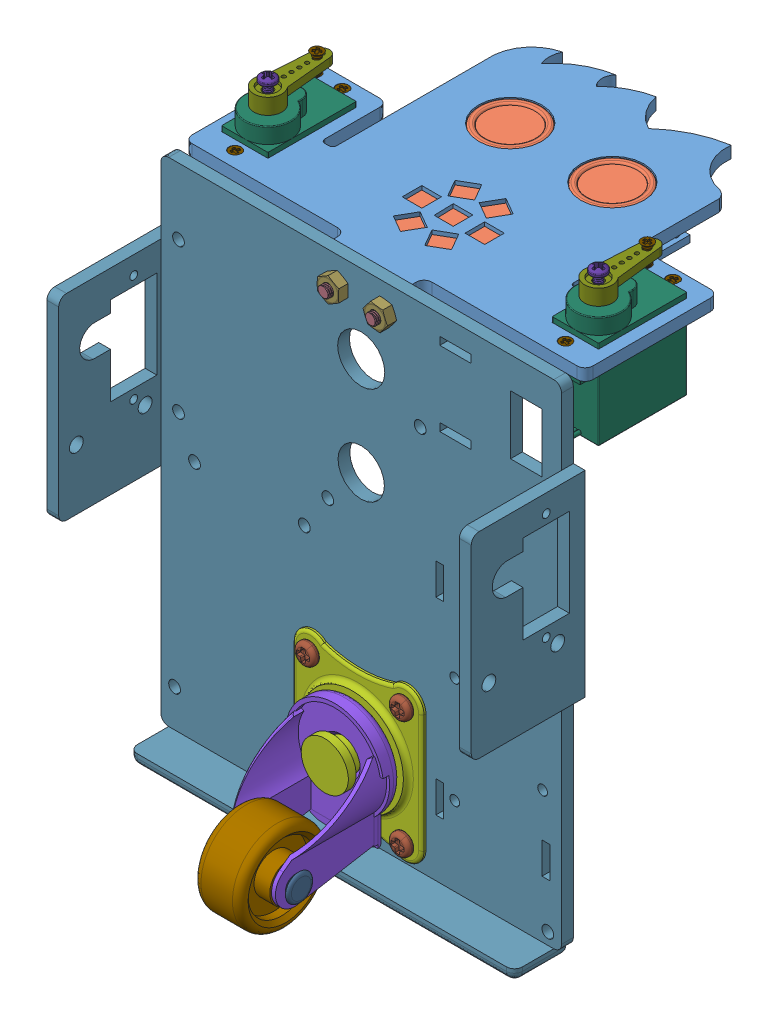
SolidWorks assembly DYOR_3D_LS_AC, configuration Predeterminado. Lengths in mm.
Overall size (108 144.05 112.97).
49 component instances, 20 part files, 16 mates.
Components (placement in the parent):
- HC-SR04 Ping Sensor-1: HC-SR04 Ping Sensor [Default] at (9.3451 28.7888 -38.4611) x (0 0 -1) z (0 1 0) size (25.18 45 18.07)
  - PCB-1: PCB [Default] at origin size (20.5 45 1.75)
  - Transducer-1: Transducer [Default] at (0 -13 13.25) x (1 0 0) z (0 -1 0) size (15.88 12 15.88)
  - Transducer-2: Transducer [Default] at (0 13 13.25) x (1 0 0) z (0 -1 0) size (15.88 12 15.88)
  - 3 Pin Header 90 Degree-1: 3 Pin Header 90 Degree [Default] at (8.4275 0 -1.25) x (-1 0 0) z (0 -1 0) size (8 7.82 10)
  - 14 Pin SMT-1: 14 Pin SMT [Default] at (-0.35 -18.5 -0.85) x (0 -1 0) z (1 0 0) size (6 1.6 8.8)
  - 14 Pin SMT-2: 14 Pin SMT [Default] at (0 -0.3826 -0.85) x (1 0 0) z (0 1 0) size (6 1.6 8.8)
  - 14 Pin SMT-3: 14 Pin SMT [Default] at (0 17.5274 -0.85) x (1 0 0) z (0 1 0) size (6 1.6 8.8)
  - Cap1 SMT-1: Cap1 SMT [Default] at (-1.755 7.4774 -0.9689) x (0 1 0) z (-1 0 0) size (4.5 1.84 1.75)
  - Cap1 SMT-2: Cap1 SMT [Default] at (6.835 7.4774 -0.9689) x (0 1 0) z (-1 0 0) size (4.5 1.84 1.75)
  - Cap1 SMT-3: Cap1 SMT [Default] at (-6.835 7.4774 -0.9689) x (0 1 0) z (-1 0 0) size (4.5 1.84 1.75)
  - Cap1 SMT-4: Cap1 SMT [Default] at (4.295 7.4774 -0.9689) x (0 1 0) z (-1 0 0) size (4.5 1.84 1.75)
  - Cap1 SMT-5: Cap1 SMT [Default] at (1.755 7.4774 -0.9689) x (0 1 0) z (-1 0 0) size (4.5 1.84 1.75)
  - Cap1 SMT-6: Cap1 SMT [Default] at (-4.295 7.4774 -0.9689) x (0 1 0) z (-1 0 0) size (4.5 1.84 1.75)
  - HC-SR04 Crystal-1: HC-SR04 Crystal [Default] at (-8.3 0 1.75) x (0 -1 0) z (0 0 1) size (10 3.5 2.7)
- CA-1: CA [Predeterminado] at (-2.207 18.0036 0) size (33 45.94 43.2)
  - Caster Wheel-1: Caster Wheel [Default] at (57.6387 -78.841 57.7572) x (0 1 0) z (-1 0 0) size (45.94 37.59 33)
    - caster holder-1: caster holder [Default] at (-24.0751 44.7184 29.5137) x (1 0 0) z (0 0 -1) size (39 9.27 33)
    - holder-1: holder [Default] at (-1.5751 42.9484 46.0137) x (0 0 1) z (1 0 0) size (25 28.07 31.31)
    - caster wheel-1: caster wheel [Default] at (-15.6961 19.9484 46.0137) x (0.997275 0.073773 0) z (0 0 1) size (23 23 14)
    - Part4-1: Part4 [Default] at (-15.6961 19.9484 55.0137) x (-0.978448 0.206495 0) z (0 0 -1) size (7 7 20)
  - M3x6 Philips Screw-1: M3x6 Philips Screw [Predeterminado] at (23.625 -65.4161 13.5389) size (5.3 5.3 7.81)
  - M3x6 Philips Screw-2: M3x6 Philips Screw [Predeterminado] at (-0.375 -65.4161 13.5389) size (5.3 5.3 7.81)
  - M3x6 Philips Screw-3: M3x6 Philips Screw [Predeterminado] at (-0.375 -95.4161 13.5389) size (5.3 5.3 7.81)
  - M3x6 Philips Screw-4: M3x6 Philips Screw [Predeterminado] at (23.625 -95.4161 13.5389) size (5.3 5.3 7.81)
  - M3 Nut-1: M3 Nut [Predeterminado] at (23.625 -65.4161 11.0389) size (6.27 6.27 2.71)
  - M3 Nut-2: M3 Nut [Predeterminado] at (-0.375 -65.4161 11.0389) size (6.27 6.27 2.71)
  - M3 Nut-3: M3 Nut [Predeterminado] at (-0.375 -95.4161 11.0389) size (6.27 6.27 2.71)
  - M3 Nut-4: M3 Nut [Predeterminado] at (23.625 -95.4161 11.0389) size (6.27 6.27 2.71)
- M3x10 Philips Screw-2: M3x10 Philips Screw [Predeterminado] at (3.418 36.0388 6.1705) x (-0.582954 -0.812505 0) z (0 0 -1) size (5.3 5.3 11.8)
- M3x10 Philips Screw-3: M3x10 Philips Screw [Predeterminado] at (15.418 36.0388 6.1705) x (-0.89856 -0.438851 0) z (0 0 -1) size (5.3 5.3 11.8)
- M3 Nut-1: M3 Nut [Predeterminado] at (3.418 36.0388 16.5389) size (6.27 6.27 2.71)
- M3 Nut-2: M3 Nut [Predeterminado] at (15.418 36.0388 11.0389) x (-0.923728 -0.383049 0) z (0 0 -1) size (6.27 6.27 2.71)
- Base-1: Base [Predeterminado] at (60.418 -80.9125 12.5389) size (108 128.45 29)
- AC-1: AC [Predeterminado] at (-137.3228 216.8523 -134.1392) size (95.94 34.06 31.9)
  - sg90-1: sg90 [Default] at (182.9409 -195.7135 134.2781) x (0 0 -1) z (1 0 0) size (31.9 29.9 11.8)
  - sg90-2: sg90 [Default] at (98.7972 -195.7135 134.2781) x (0 0 -1) z (1 0 0) size (31.9 29.9 11.8)
  - SG90 plastic Horn-1: SG90 plastic Horn [Default] at (188.8409 -166.2635 128.3781) x (-0.029359 0 -0.999569) z (0.999569 0 -0.029359) size (19.4 4 7.07)
  - SG90 plastic Horn-2: SG90 plastic Horn [Default] at (104.6972 -166.2635 128.3781) x (-0.012387 0 -0.999923) z (0.999923 0 -0.012387) size (19.4 4 7.07)
  - (M2_3_mm)_90116A007_METRIC 316 SS PAN HEAD PHILLIPS MACHINE SCREW-1: (M2_3_mm)_90116A007_METRIC 316 SS PAN HEAD PHILLIPS MACHINE SCREW [90116A007] at (104.6972 -166.2635 128.3781) x (-1 0 0) z (0 1 0) size (4 4 4.68)
  - (M2_3_mm)_90116A007_METRIC 316 SS PAN HEAD PHILLIPS MACHINE SCREW-2: (M2_3_mm)_90116A007_METRIC 316 SS PAN HEAD PHILLIPS MACHINE SCREW [90116A007] at (188.8409 -166.2635 128.3781) x (-1 0 0) z (0 1 0) size (4 4 4.68)
  - M2x6 SelfTap Screw-1: M2x6 SelfTap Screw [Predeterminado] at (104.6972 -162.7635 115.8781) x (0.825172 0 -0.564882) z (0 1 0) size (3.4 3.28 6)
  - M2x6 SelfTap Screw-2: M2x6 SelfTap Screw [Predeterminado] at (188.7787 -162.7635 115.8783) x (0.001298 0 -0.999999) z (0 1 0) size (3.4 3.28 6)
  - M2x6 SelfTap Screw-3: M2x6 SelfTap Screw [Predeterminado] at (104.6972 -174.3135 109.3781) x (-0.923728 0 -0.383049) z (0 1 0) size (3.4 3.28 6)
  - M2x6 SelfTap Screw-4: M2x6 SelfTap Screw [Predeterminado] at (104.6972 -174.3135 136.6781) x (-0.923728 0 -0.383049) z (0 1 0) size (3.4 3.28 6)
  - M2x6 SelfTap Screw-5: M2x6 SelfTap Screw [Predeterminado] at (188.8409 -174.3135 136.6781) x (0.923728 0 0.383049) z (0 1 0) size (3.4 3.28 6)
  - M2x6 SelfTap Screw-6: M2x6 SelfTap Screw [Predeterminado] at (188.8409 -174.3135 109.3781) x (0.923728 0 0.383049) z (0 1 0) size (3.4 3.28 6)
- Front_LS_AC-1: Front_LS_AC [Predeterminado] at (-51.3538 39.5388 -46.4821) x (1 0 0) z (0 1 0) size (101.94 72.38 11)
- ws8212-7-1: ws8212-7 [Predeterminado] at (9.3451 38.5388 -10.9611) x (0 0 -1) z (0 1 0) size (24 24 3.1)
Mates (geometry in assembly coordinates):
- Concéntrica15: concentric: circle of CA-1/Caster Wheel-1/caster holder-1; circle of Base-1
- Coincidente14: coincident: plane of CA-1/M3 Nut-4 through (21.418 -77.4125 9.5389) normal (0 0 1); plane of Base-1 through (-39.582 40.5388 9.5389) normal (0 0 -1)
- Concéntrica16: concentric: circle of CA-1/M3 Nut-1; circle of Base-1
- Coincidente26: coincident: plane of M3 Nut-2 through (15.418 36.0388 12.5389) normal (0 0 -1); plane of Base-1 through (-39.582 40.5388 12.5389) normal (0 0 1)
- Coincidente27: coincident: plane of M3 Nut-1 through (3.418 36.0388 12.5389) normal (0 0 -1); plane of Base-1 through (-39.582 40.5388 12.5389) normal (0 0 1)
- Concéntrica22: concentric: circle of M3 Nut-1; circle of Base-1
- Concéntrica23: concentric: circle of M3 Nut-2; circle of Base-1
- Coincidente28: coincident: plane of Base-1 through (-39.582 40.5388 9.5389) normal (0 0 -1); plane of Front_LS_AC-1 through (-0.582 42.5388 9.5389) normal (0 0 1)
- Concéntrica24: concentric: circle of Base-1; circle of Front_LS_AC-1
- Paralelo1: parallel: plane of Base-1 through (-39.582 42.5388 9.5389) normal (0 1 0); plane of Front_LS_AC-1 through (40.5899 42.5388 -11.4111) normal (0 1 0)
- Concéntrica25: concentric: circle of HC-SR04 Ping Sensor-1/Transducer-1; circle of Front_LS_AC-1
- Concéntrica26: concentric: circle of HC-SR04 Ping Sensor-1/Transducer-2; circle of Front_LS_AC-1
- Coincidente30: coincident: plane of HC-SR04 Ping Sensor-1/Transducer-2 through (-3.6549 42.5388 -46.4011) normal (0 1 0); plane of Front_LS_AC-1 through (40.5899 42.5388 -11.4111) normal (0 1 0)
- Coincidente31: coincident: plane of Front_LS_AC-1 through (3.8451 42.5388 -13.4611) normal (0 0 1); plane of ws8212-7-1 through (-1.1549 41.5388 -13.4611) normal (0 0 -1)
- Coincidente32: coincident: plane of Front_LS_AC-1 through (3.8451 42.5388 -8.4611) normal (-1 0 0); plane of ws8212-7-1 through (3.8451 41.5388 -13.4611) normal (1 0 0)
- Distancia1: distance = 1 mm: plane of ws8212-7-1 through (9.3451 41.5388 -10.9611) normal (0 1 0); plane of Front_LS_AC-1 through (40.5899 42.5388 -11.4111) normal (0 1 0)
